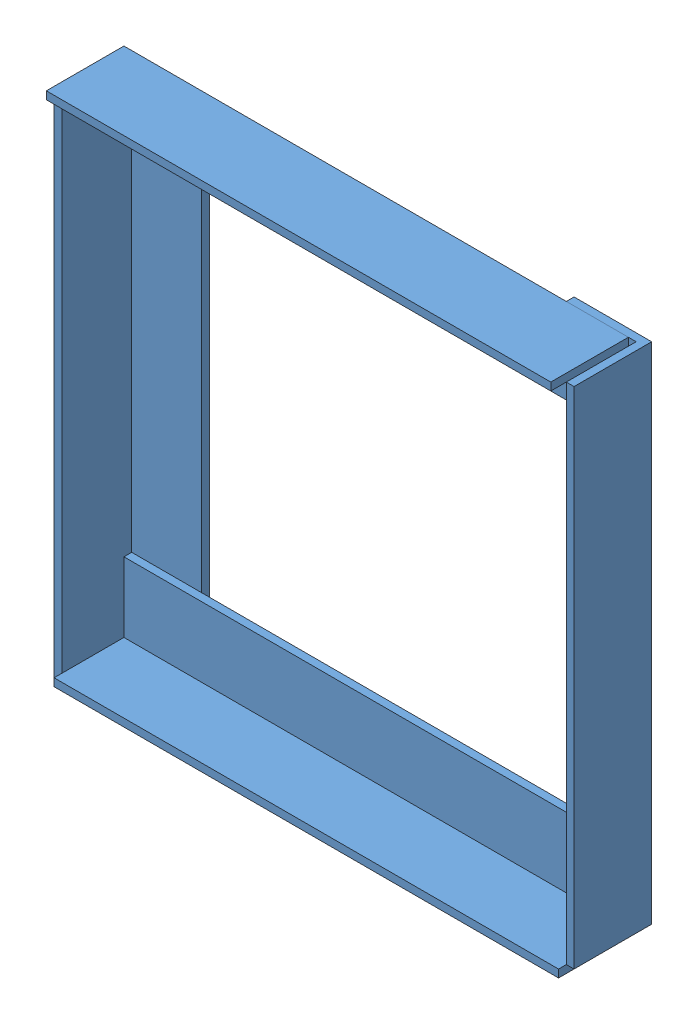
SolidWorks assembly Assem2, configuration Default. Lengths in mm.
Overall size (268 264 44).
4 component instances, 1 part files, 10 mates.
Components (placement in the parent):
- 2-1: 2 [Default] at (126.2659 174.5818 137.7283) size (40 260 40)
- 2-2: 2 [Default] at (236.2659 288.5818 141.7283) x (0 -1 0) z (0 0 1) size (40 260 40)
- 2-3: 2 [Default] at (354.2659 178.5818 137.7283) x (-1 0 0) z (0 0 1) size (40 260 40)
- 2-4: 2 [Default] at (240.2659 64.5818 141.7283) x (0 1 0) z (0 0 1) size (40 260 40)
Mates (geometry in assembly coordinates):
- Coincident1: coincident: plane of 2-1 through (110.2659 174.5818 177.7283) normal (1 0 0); line of 2-4 through (110.2659 48.5818 181.7283) axis (0 0 -1)
- Coincident2: coincident anti-aligned: plane of 2-1 through (110.2659 174.5818 177.7283) normal (1 0 0); plane of 2-4 through (110.2659 64.5818 145.7283) normal (-1 0 0)
- Coincident3: coincident aligned: plane of 2-4 through (240.2659 44.5818 181.7283) normal (0 -1 0); plane of 2-1 through (126.2659 44.5818 141.7283) normal (0 -1 0)
- Coincident4: coincident anti-aligned: plane of 2-4 through (240.2659 64.5818 141.7283) normal (0 0 -1); plane of 2-1 through (126.2659 174.5818 141.7283) normal (0 0 1)
- Coincident6: coincident anti-aligned: plane of 2-1 through (126.2659 304.5818 141.7283) normal (0 1 0); plane of 2-2 through (236.2659 304.5818 181.7283) normal (0 -1 0)
- Coincident8: coincident aligned: plane of 2-1 through (106.2659 174.5818 177.7283) normal (-1 0 0); plane of 2-2 through (106.2659 288.5818 145.7283) normal (-1 0 0)
- Coincident11: coincident anti-aligned: plane of 2-3 through (370.2659 174.5818 177.7283) normal (-1 0 0); plane of 2-4 through (370.2659 64.5818 145.7283) normal (1 0 0)
- Coincident15: coincident anti-aligned: plane of 2-1 through (126.2659 174.5818 141.7283) normal (0 0 1); plane of 2-2 through (236.2659 288.5818 141.7283) normal (0 0 -1)
- Coincident16: coincident anti-aligned: plane of 2-3 through (354.2659 174.5818 141.7283) normal (0 0 1); plane of 2-4 through (240.2659 64.5818 141.7283) normal (0 0 -1)
- Coincident18: coincident aligned: plane of 2-2 through (236.2659 308.5818 181.7283) normal (0 1 0); plane of 2-3 through (354.2659 308.5818 141.7283) normal (0 1 0)
